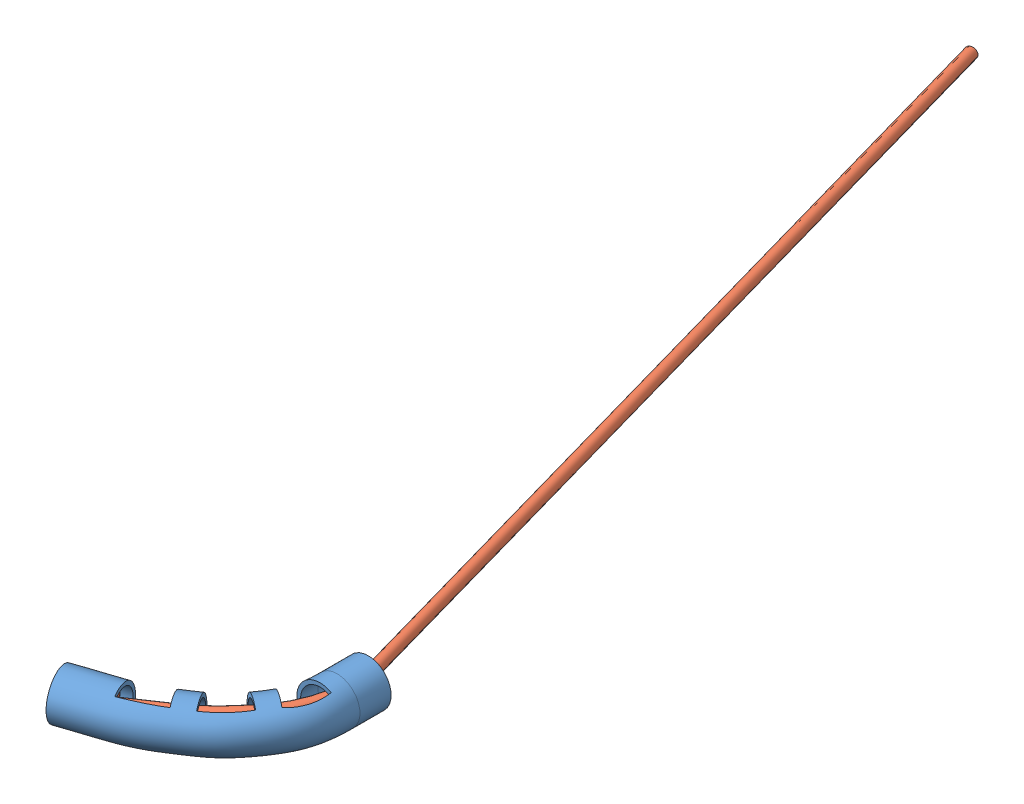
SolidWorks assembly cable + square joint_curve 3 assem, configuration Default. Lengths in mm.
Overall size (19.37 1.4 28.07).
2 component instances, 2 part files, 1 mates.
Components (placement in the parent):
- Arushri_Tube_SquareJoint_curve 3-1: Arushri_Tube_SquareJoint_curve 3 [Default] at (3.3174 3.4786 2.5513) size (4.78 1.4 15.36)
- cable_curve3-1: cable_curve3 [Default] at (0.023 3.4786 6.3562) x (-0.435084 0 -0.90039) z (0 1 0) size (26.06 8.92 0.5)
Mates (geometry in assembly coordinates):
- Coincident1: coincident anti-aligned: circle of Arushri_Tube_SquareJoint_curve 3-1; circle of cable_curve3-1
